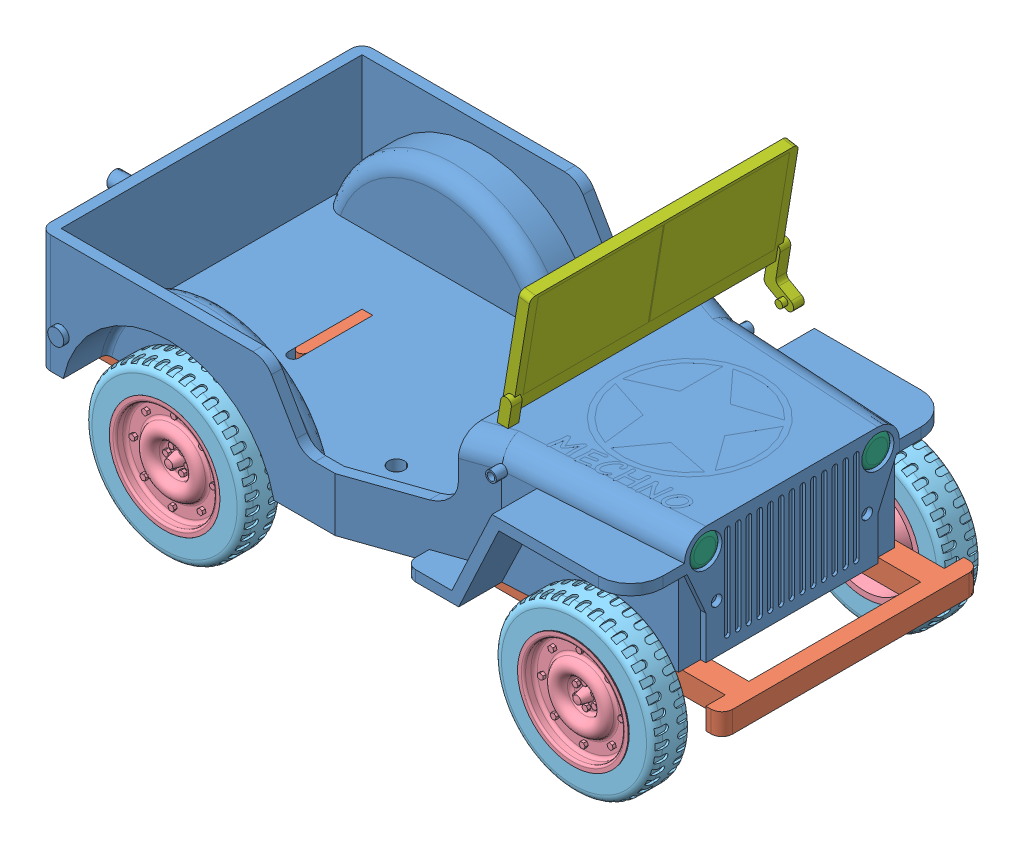
SolidWorks assembly Assem1, configuration Default. Lengths in mm.
Overall size (649.92 326.61 321.58).
15 component instances, 7 part files, 21 mates.
Components (placement in the parent):
- body-1: body [Default] at (51.746 272.327 366.6521) size (570 110.01 305)
- chessis-1: chessis [Default] at (36.746 242.327 361.6299) size (649.92 50 240)
- rod-1: rod [Default] at (551.6647 242.327 361.6299) x (0.999999 0.001508 0) z (0 0 -1) size (15 15 275)
- rod-2: rod [Default] at (171.746 242.327 361.6299) x (0.002046 0.999998 0) z (0 0 1) size (15 15 275)
- rim-1: rim [Default] at (551.6647 242.327 499.1299) x (0 0 -1) z (0.999122 0.041902 0) size (48.72 103 103)
- tyre-1: tyre [Default] at (551.6647 242.327 501.8454) x (0 0 -1) z (0.137503 -0.990501 0) size (35 150.73 150.73)
- rim-2: rim [Default] at (171.746 242.327 499.1299) x (0 0 -1) z (-0.027589 -0.999619 0) size (48.72 103 103)
- tyre-2: tyre [Default] at (171.746 242.327 502.8454) x (0 0 -1) z (-0.028453 -0.999595 0) size (35 150.73 150.73)
- tyre-8: tyre [Default] at (171.746 242.327 230.4589) x (0 0 1) z (0.028453 0.999595 0) size (35 150.73 150.73)
- rim-7: rim [Default] at (171.746 242.327 234.1744) x (0 0 1) z (0.027589 0.999619 0) size (48.72 103 103)
- rim-8: rim [Default] at (551.6647 242.327 234.1744) x (0 0 1) z (-0.999122 -0.041902 0) size (48.72 103 103)
- tyre-9: tyre [Default] at (551.6647 242.327 231.4589) x (0 0 1) z (-0.137503 0.990501 0) size (35 150.73 150.73)
- headlight-1: headlight [Default] at (596.746 352.327 286.6521) x (-1 0 0) z (0 -0.250637 0.968081) size (4 30 30)
- headlight-2: headlight [Default] at (596.746 352.327 446.6521) x (-1 0 0) z (0 -0.250637 0.968081) size (4 30 30)
- wind sheild-1: wind sheild [Default] at (430.0983 381.8543 330.0711) x (0.986692 -0.1626 0) z (0 0 1) size (31.29 134.04 260)
Mates (geometry in assembly coordinates):
- Concentric8: concentric aligned: cylinder of body-1 through (551.746 277.327 391.6299) axis (0 -1 0) radius 5; cylinder of chessis-1 through (551.746 272.327 391.6299) axis (0 -1 0) radius 5
- Coincident5: coincident anti-aligned: plane of body-1 through (176.746 277.327 340.496) normal (-1 0 0); plane of chessis-1 through (176.746 272.327 331.6299) normal (1 0 0)
- Coincident6: coincident anti-aligned: plane of body-1 through (61.746 262.327 226.6521) normal (0 -1 0); plane of chessis-1 through (36.746 262.327 361.6299) normal (0 1 0)
- Coincident7: coincident aligned: cylinder of chessis-1 through (551.6647 242.327 246.6299) axis (0 0 1) radius 7.5; circle of rod-1
- Width2: width aligned: plane of chessis-1 through (36.746 242.327 471.6299) normal (0 0 1); plane of chessis-1 through (36.746 242.327 251.6299) normal (0 0 -1); plane of rod-1 through (551.6647 242.327 499.1299) normal (0 0 1); plane of rod-1 through (551.6647 242.327 224.1299) normal (0 0 -1)
- Coincident9: coincident anti-aligned: circle of chessis-1; cylinder of rod-2 through (171.746 242.327 499.1299) axis (0 0 -1) radius 7.5
- Width3: width anti-aligned: plane of chessis-1 through (36.746 242.327 471.6299) normal (0 0 1); plane of chessis-1 through (36.746 242.327 251.6299) normal (0 0 -1); plane of rod-2 through (171.746 242.327 224.1299) normal (0 0 -1); plane of rod-2 through (171.746 242.327 499.1299) normal (0 0 1)
- Concentric10: concentric aligned: circle of rim-1; cylinder of tyre-1 through (551.6647 242.327 501.8454) axis (0 0 -1) radius 50
- Coincident12: coincident aligned: plane of rim-1 through (551.6647 242.327 484.3454) normal (0 0 -1); plane of tyre-1 through (618.5235 251.6084 484.3454) normal (0 0 -1)
- Concentric11: concentric aligned: cone of rod-1 through (551.6647 242.327 224.1299) axis (0 0 -1); cylinder of rim-1 through (551.6647 242.327 499.1299) axis (0 0 -1) radius 7.5
- Coincident13: coincident anti-aligned: plane of chessis-1 through (36.746 242.327 471.6299) normal (0 0 1); plane of rim-1 through (551.6647 242.327 471.6299) normal (0 0 -1)
- Concentric12: concentric aligned: cone of rim-2 through (171.746 242.327 519.8454) axis (0 0 -1); cylinder of tyre-2 through (171.746 242.327 502.8454) axis (0 0 -1) radius 50
- Coincident14: coincident aligned: plane of rim-2 through (171.746 242.327 520.3454) normal (0 0 1); plane of tyre-2 through (221.7257 240.9044 520.3454) normal (0 0 1)
- Coincident15: coincident anti-aligned: plane of chessis-1 through (36.746 242.327 471.6299) normal (0 0 1); plane of rim-2 through (171.746 242.327 471.6299) normal (0 0 -1)
- Coincident16: coincident anti-aligned: plane of chessis-1 through (36.746 242.327 471.6299) normal (0 0 1); plane of rim-2 through (171.746 242.327 471.6299) normal (0 0 -1)
- Coincident17: coincident anti-aligned: plane of chessis-1 through (36.746 242.327 471.6299) normal (0 0 1); plane of rim-2 through (171.746 242.327 471.6299) normal (0 0 -1)
- Concentric13: concentric aligned: cylinder of rod-2 through (171.746 242.327 499.1299) axis (0 0 -1) radius 7.5; cylinder of rim-2 through (171.746 242.327 499.1299) axis (0 0 -1) radius 7.5
- Coincident24: coincident aligned: circle of body-1; circle of headlight-1
- Concentric15: concentric anti-aligned: circle of body-1; circle of headlight-2
- Coincident26: coincident anti-aligned: circle of body-1; circle of headlight-2
- Concentric16: concentric aligned: cylinder of body-1 through (441.746 352.327 -499633.3479) axis (0 0 1) radius 3.5; cylinder of wind sheild-1 through (441.746 352.327 445.0711) axis (0 0 1) radius 3.5
